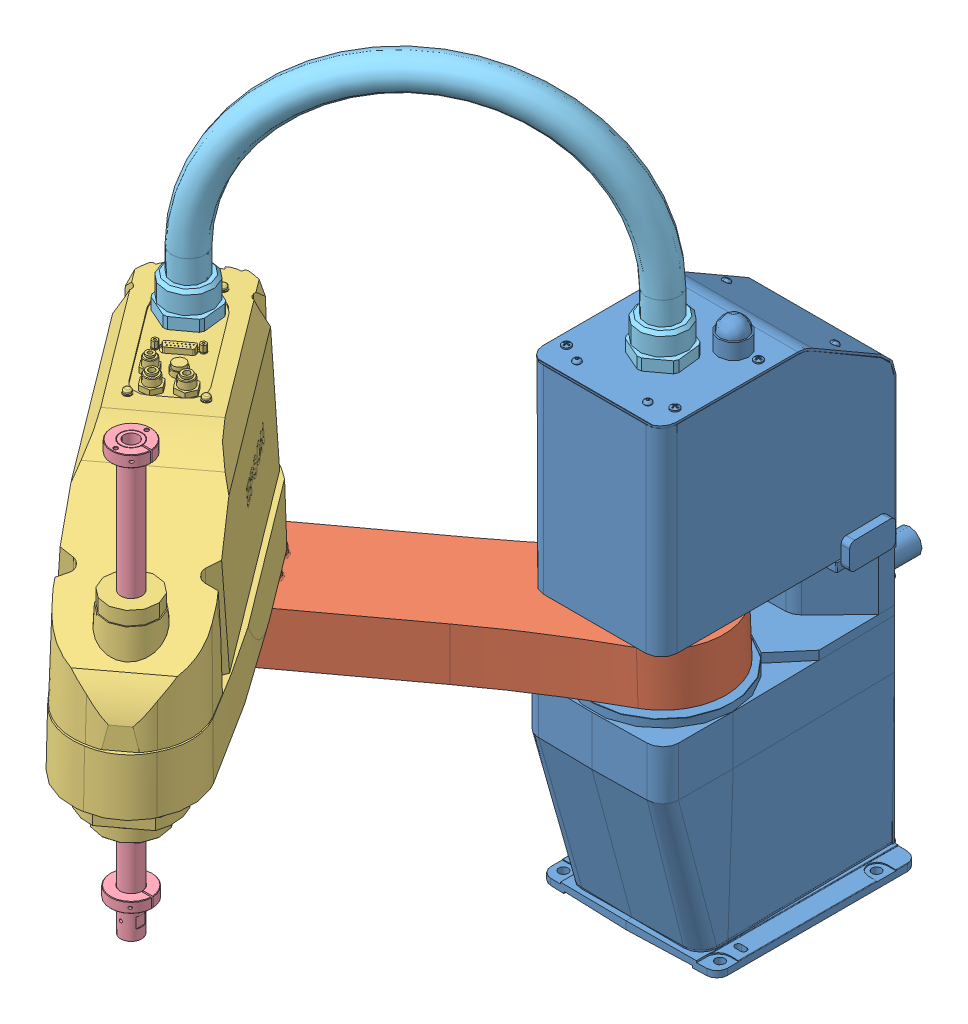
SolidWorks assembly T6-602S, configuration Default. Lengths in mm.
Overall size (437.85 696.6 710.15).
6 component instances, 6 part files, 14 mates.
Components (placement in the parent):
- _T6-602S_BASE_1_2-1: _T6-602S_BASE_1_2 [Default] x (0 0 1) z (-1 0 0) size (277.81 491 169.01)
- _T6-602S_ARM1_1_2-1: _T6-602S_ARM1_1_2 [Default] at (0 200 62.5) x (-0.805129 0 0.5931) z (-0.5931 0 -0.805129) size (440.55 67 122.71)
- _T6-602S_ARM2_1_2-1: _T6-602S_ARM2_1_2 [Default] at (-96.5718 265 475.1859) x (0.600346 0 0.79974) z (-0.79974 0 0.600346) size (392.25 248.41 135.51)
- _T6-602S_SHAFT_1_2-1: _T6-602S_SHAFT_1_2 [Default] at (-96.5718 529.386 475.1859) x (0.999968 0 -0.007955) z (0.007955 0 0.999968) size (39.99 410 40)
- _T6-602S_CABLE_1_2-1: _T6-602S_CABLE_1_2 [Default] at (-261.667 441.3 255.2573) x (0.5931 0 0.805129) z (-0.805129 0 0.5931) size (46.1 245.8 375.7)
- _T6-602SWS-1: _T6-602SWS [Default] x (0 0 -1) z (1 0 0) size (1092.5 200 1200) (hidden)
Mates (geometry in assembly coordinates):
- Coincident2: coincident: point of _T6-602S_BASE_1_2-1
- Coincident3: coincident aligned: plane of _T6-602S_BASE_1_2-1 through (0 0 0) normal (0 1 0)
- Coincident4: coincident anti-aligned: plane of _T6-602S_BASE_1_2-1 through (0 0 0) normal (-1 0 0)
- Coincident5: coincident aligned: plane of _T6-602SWS-1 through (0 0 0) normal (1 0 0)
- Coincident6: coincident aligned: plane of _T6-602SWS-1 through (0 0 0) normal (0 1 0)
- Coincident7: coincident anti-aligned: plane of _T6-602S_BASE_1_2-1 through (0 0 0) normal (0 0 1); plane of _T6-602SWS-1 through (0 0 0) normal (0 0 -1)
- Coincident8: coincident aligned: line of _T6-602S_BASE_1_2-1 through (0 206.4987 62.5) axis (0 1 0); line of _T6-602S_ARM1_1_2-1 through (0 200 62.5) axis (0 1 0)
- Coincident9: coincident anti-aligned: plane of _T6-602S_BASE_1_2-1 through (44 228 62.5) normal (0 1 0); plane of _T6-602S_ARM1_1_2-1 through (26.0964 228 97.9257) normal (0 -1 0)
- Coincident10: coincident aligned: line of _T6-602S_ARM1_1_2-1 through (-261.667 220 255.2573) axis (0 1 0); line of _T6-602S_ARM2_1_2-1 through (-261.667 219.9975 255.2573) axis (0 1 0)
- Coincident11: coincident anti-aligned: plane of _T6-602S_ARM1_1_2-1 through (-234.9775 220 291.4882) normal (0 1 0); plane of _T6-602S_ARM2_1_2-1 through (-225.6787 220 228.2418) normal (0 -1 0)
- Coincident12: coincident aligned: line of _T6-602S_ARM2_1_2-1 through (-96.5718 224.9987 475.1859) axis (0 1 0); line of _T6-602S_SHAFT_1_2-1 through (-96.5718 130.386 475.1859) axis (0 1 0)
- Concentric1: concentric anti-aligned: cylinder of _T6-602S_BASE_1_2-1 through (0 486.3 62.5) axis (0 -1 0) radius 18.5; line of _T6-602S_CABLE_1_2-1 through (0 441.3 62.5) axis (0 1 0)
- Coincident13: coincident anti-aligned: plane of _T6-602S_BASE_1_2-1 through (-63.75 453.5 126.9) normal (0 1 0); plane of _T6-602S_CABLE_1_2-1 through (20.41 453.5 47.4649) normal (0 -1 0)
- Concentric2: concentric aligned: cylinder of _T6-602S_ARM2_1_2-1 through (-261.667 486.3 255.2573) axis (0 -1 0) radius 18.5; cylinder of _T6-602S_CABLE_1_2-1 through (-261.667 486.3 255.2573) axis (0 -1 0) radius 18.5
